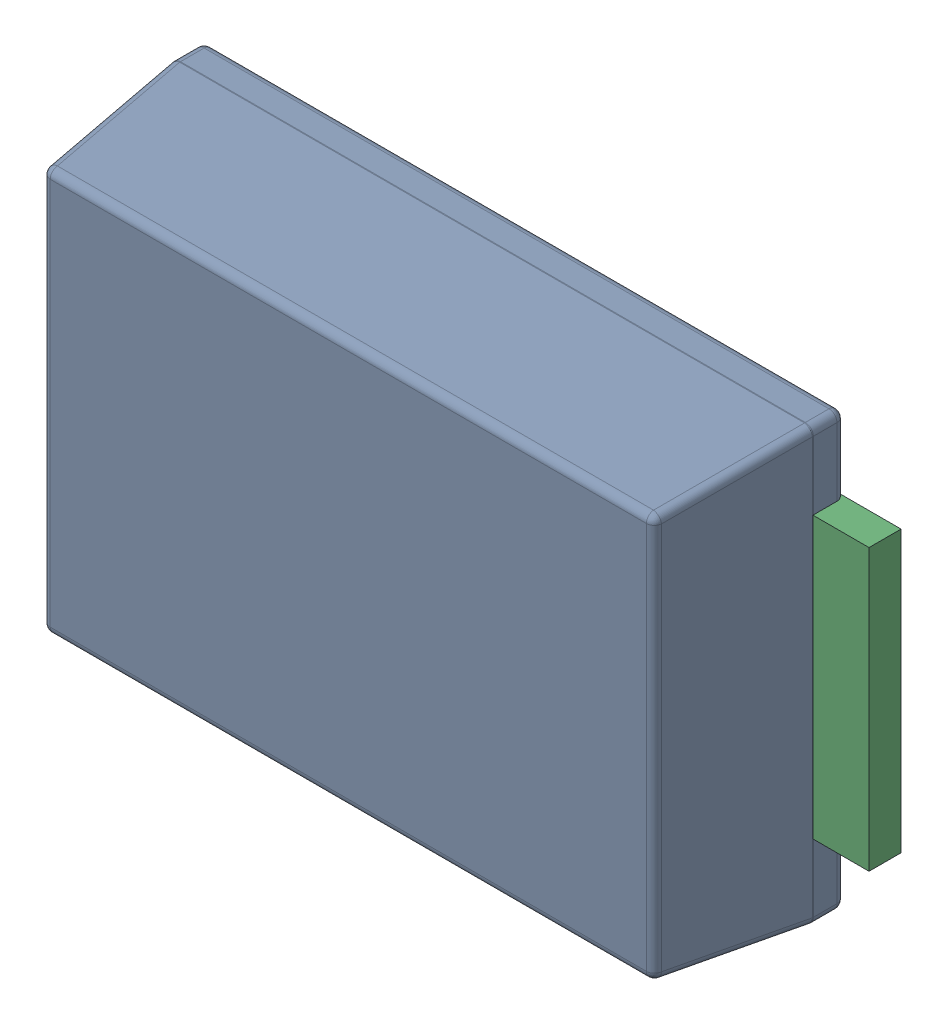
SolidWorks assembly D5, configuration Default. Lengths in mm.
Overall size (4.7 2.71 1.1).
5 component instances, 2 part files, 0 mates.
Components (placement in the parent):
- 1281330688-1: 1281330688 [Default] at (102.8713 61.722 0) x (1 0 0) z (0 0 1) size (4.7 2.71 1.1)
  - Body-1: Body [Default] at (-2 -1.35 0) size (4.01 2.71 1.1)
    - Open_CASCADE_STEP_translator_6.8_1.1.1-1: Open_CASCADE_STEP_translator_6.8_1.1.1 [Default] at origin size (4.01 2.71 1.1)
  - lead-1: lead [Default] at (-2.35 -0.875 0) size (0.72 1.75 0.2)
  - lead-2: lead [Default] at (2.35 0.875 0) x (-1 0 0) z (0 0 1) size (0.72 1.75 0.2)
